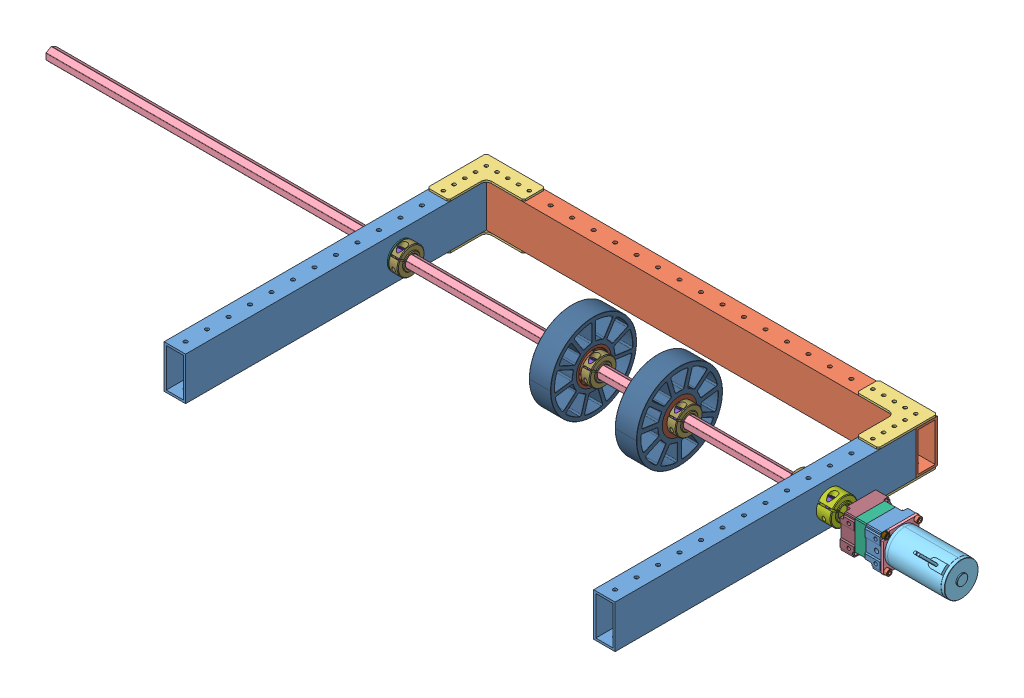
SolidWorks assembly New Intake, configuration Default. Lengths in mm.
Overall size (1077.8 101.6 381).
71 component instances, 30 part files, 56 mates.
Components (placement in the parent):
- 14 in new versaplanetary frame - rev2-1: 14 in new versaplanetary frame - rev2 [Default] at (737.2881 12.7 38.1) x (0 -1 0) z (0 0 -1) size (50.8 25.4 355.6)
- 14 in new versaplanetary frame - rev2-2: 14 in new versaplanetary frame - rev2 [Default] at (1245.2881 12.7 38.1) x (0 1 0) z (0 0 -1) size (50.8 25.4 355.6)
- 21 in new versaplanetary frame - rev2-3: 21 in new versaplanetary frame - rev2 [Default] at (724.5881 12.7 25.4) x (0 -1 0) z (-1 0 0) size (50.8 25.4 533.4)
- VersaFrame 90 Degree Gusset (217-3548).step-1: VersaFrame 90 Degree Gusset (217-3548).step [Default] at (737.2881 -14.986 25.4) x (1 0 0) z (0 1 0) size (69.72 69.72 2.29)
- VersaFrame 90 Degree Gusset (217-3548).step-2: VersaFrame 90 Degree Gusset (217-3548).step [Default] at (737.2881 38.1 25.4) x (1 0 0) z (0 1 0) size (69.72 69.72 2.29)
- VersaFrame 90 Degree Gusset (217-3548).step-3: VersaFrame 90 Degree Gusset (217-3548).step [Default] at (1245.2881 -12.7 25.4) x (-1 0 0) z (0 -1 0) size (69.72 69.72 2.29)
- VersaFrame 90 Degree Gusset (217-3548).step-4: VersaFrame 90 Degree Gusset (217-3548).step [Default] at (1245.2881 40.386 25.4) x (-1 0 0) z (0 -1 0) size (69.72 69.72 2.29)
- half inch hex shaft 36 in long.step-1: half inch hex shaft 36 in long.step [Default] at (794.4381 12.6853 139.7) x (0 -1 0) z (1 0 0) size (14.48 12.67 914.4)
- bearing_0.5in_flangedhex-1: bearing_0.5in_flangedhex [Default] at (1238.4835 12.7 139.7) x (0 0.5 -0.866025) z (-1 0 0) size (31.12 31.12 7.93)
- Half inch flange bearing.step-1: Half inch flange bearing.step [Default] at (743.5848 12.7 139.7) x (0 0 -1) z (1 0 0) size (31.12 31.12 7.93)
- am-1560 500Hex and 500Key Coupler.STEP-1: am-1560 500Hex and 500Key Coupler.STEP [Default] at (1237.7215 21.1345 153.1152) x (1 0 0) z (0 -0.5 -0.866025) size (38.1 31.75 31.68)
  - 500Hex and Key Coupler.STEP-1: 500Hex and Key Coupler.STEP [Default] at (19.05 1.016 15.8425) x (0 0 1) z (-1 0 0) size (31.68 14.86 38.1)
  - 500Hex and Key Coupler.STEP-2: 500Hex and Key Coupler.STEP [Default] at (19.05 1.016 15.8425) x (0 0 -1) z (-1 0 0) size (31.68 14.86 38.1)
  - 10-32x0500_shcs_HX-SHCS 0.19-32x1.375x1-C.STEP-1: 10-32x0500_shcs_HX-SHCS 0.19-32x1.375x1-C.STEP [Default] at (9.525 -8.001 4.73) x (0 1 0) z (-0.057029 0 0.998373) size (17.53 7.94 7.94)
  - 10-32x0500_shcs_HX-SHCS 0.19-32x1.375x1-C.STEP-2: 10-32x0500_shcs_HX-SHCS 0.19-32x1.375x1-C.STEP [Default] at (28.575 -8.001 4.73) x (0 1 0) z (-0.057029 0 0.998373) size (17.53 7.94 7.94)
  - 10-32x0500_shcs_HX-SHCS 0.19-32x1.375x1-C.STEP-3: 10-32x0500_shcs_HX-SHCS 0.19-32x1.375x1-C.STEP [Default] at (28.575 10.033 26.955) x (0 -1 0) z (-0.057029 0 0.998373) size (17.53 7.94 7.94)
  - 10-32x0500_shcs_HX-SHCS 0.19-32x1.375x1-C.STEP-4: 10-32x0500_shcs_HX-SHCS 0.19-32x1.375x1-C.STEP [Default] at (9.525 10.033 26.955) x (0 -1 0) z (-0.057029 0 0.998373) size (17.53 7.94 7.94)
- VersaPlanetary v2 Single Stage 10_1 with BAG .step-1: VersaPlanetary v2 Single Stage 10_1 with BAG .step [Default] at (1308.8383 12.2234 161.9377) x (-1 0 0) z (0 -1 0) size (163.4 66.46 65.46)
  - 217-2820 Rev1_Public.step-1: 217-2820 Rev1_Public.step [Default] at (-4.6546 22.225 0) x (0 -0.456494 0.889726) z (-1 0 0) size (39.22 38.88 17.4)
    - 217-2625-100.step-1: 217-2625-100.step [Default] at origin size (39.22 38.88 12.7)
      - 217-2625-008 Rev1.step-1: 217-2625-008 Rev1.step [Default] at origin size (34.7 34.7 4.7)
      - 217-2625-010 Rev1.step-1: 217-2625-010 Rev1.step [Default] at (0 10.193 3.65) x (0.999813 0.019336 0) z (0 0 1) size (4 4 12)
      - 217-2625-010 Rev1.step-2: 217-2625-010 Rev1.step [Default] at (8.691 -5.3258 3.65) size (4 4 12)
      - 217-2625-010 Rev1.step-3: 217-2625-010 Rev1.step [Default] at (-8.691 -5.3258 3.65) size (4 4 12)
      - 217-2625-005 Rev1_Planet_Revolving_Follower01.step-1: 217-2625-005 Rev1_Planet_Revolving_Follower01.step [Default] at (8.691 -5.3258 6.35) x (0.932816 0.360354 0) z (0 0 1) size (16.89 16.89 8)
      - 217-2625-005 Rev1_Planet_Revolving_Follower01.step-2: 217-2625-005 Rev1_Planet_Revolving_Follower01.step [Default] at (-8.691 -5.3258 6.35) x (-0.932788 -0.360426 0) z (0 0 1) size (16.89 16.89 8)
      - 217-2625-005 Rev1_Planet_Revolving_Follower01.step-3: 217-2625-005 Rev1_Planet_Revolving_Follower01.step [Default] at (0 10.193 6.35) x (0.893583 0.448898 0) z (0 0 1) size (16.89 16.89 8)
    - 217-2625-007 Rev1_Public.step-1: 217-2625-007 Rev1_Public.step [Default] at (0 0 6.7) x (0.992772 0.120019 0) z (0 0 1) size (15.27 15.27 12.7)
  - 217-2625-026 Rev1.step-1: 217-2625-026 Rev1.step [Default] at (-6.5 22.225 0) x (0 -1 0) z (-1 0 0) size (44.45 42 18.12)
  - 217-2742-001 Rev4.step-1: 217-2742-001 Rev4.step [Default] at (0.2002 22.225 0) x (1 0 0) z (0 -0.092627 0.995701) size (7 28 28)
  - 217-2742-001 Rev4.step-2: 217-2742-001 Rev4.step [Default] at (8.2002 22.225 0) size (7 28 28)
  - 217-2625-017 Rev1_9714K61.step-1: 217-2625-017 Rev1_9714K61.step [Default] at (7.42 22.3002 -0.342) x (0 0.56703 0.823697) z (0 -0.823697 0.56703) size (28.51 4.98 27.43)
  - 217-2625-003 Rev1.step-1: 217-2625-003 Rev1.step [Default] at (7.4478 22.225 0) x (0 -1 0) z (1 0 0) size (17 17 64.11)
  - 217-2625-018 Rev1_98541A410.step-1: 217-2625-018 Rev1_98541A410.step [Default] at (-0.7046 22.225 0) x (1 0 0) z (0 -0.017452 0.999848) size (1 19.6 17.4)
  - 832-1750-Ring-Gear-Screw_SSA0832-0500ZC.step-1: 832-1750-Ring-Gear-Screw_SSA0832-0500ZC.step [Default] at (-30.7 4.725 -17.5) x (0 0.997447 0.071411) z (0 -0.071411 0.997447) size (6.73 48.51 6.73)
  - 832-1750-Ring-Gear-Screw_SSA0832-0500ZC.step-2: 832-1750-Ring-Gear-Screw_SSA0832-0500ZC.step [Default] at (-30.7 39.725 17.5) x (0 0.005929 0.999982) z (0 -0.999982 0.005929) size (6.73 48.51 6.73)
  - 217-2625-025 Rev1.step-1: 217-2625-025 Rev1.step [Default] at (-23.2 22.225 0) x (0 -1 0) z (-1 0 0) size (44.45 42 18)
  - 217-4649-002 Rev1_SSA0832-0500ZC.step-1: 217-4649-002 Rev1_SSA0832-0500ZC.step [Default] at (-33.7 4.2645 17.9605) x (0 0.33842 -0.940995) z (0 0.940995 0.33842) size (6.73 16.76 6.73)
  - 217-4649-002 Rev1_SSA0832-0500ZC.step-2: 217-4649-002 Rev1_SSA0832-0500ZC.step [Default] at (-33.7 40.1855 -17.9605) x (0 -0.308932 -0.951084) z (0 0.951084 -0.308932) size (6.73 16.76 6.73)
  - 217-4649-006 Rev1_SSA0004-008BA.step-1: 217-4649-006 Rev1_SSA0004-008BA.step [Default] at (-30.7 22.225 12.5) x (0 0.5 -0.866025) z (0 -0.866025 -0.5) size (7 14 7)
  - 217-4649-006 Rev1_SSA0004-008BA.step-2: 217-4649-006 Rev1_SSA0004-008BA.step [Default] at (-30.7 22.225 -12.5) x (0 -0.5 0.866025) z (0 0.866025 0.5) size (7 14 7)
  - 217-2822-003 Rev4.step-1: 217-2822-003 Rev4.step [Default] at (-32.2 22.225 0) x (0 -1 0) z (-1 0 0) size (42 42 4.8)
  - 217-3351 Rev2.step-1: 217-3351 Rev2.step [Default] at (-33.7 22.225 0) x (0 0 1) z (1 0 0) size (59.07 59.07 84.5)
  - 217-2816-001 Rev1.step-1: 217-2816-001 Rev1.step [Default] at (-6.35 22.225 0) x (0 -1 0) z (1 0 0) size (42 42 14.51)
  - 217-4649-001 Rev1.step-1: 217-4649-001 Rev1.step [Default] at (-20.046 22.225 0) x (0 -1 0) z (1 0 0) size (18 18 13)
  - 217-4649-007 Rev1_94105A824.step-1: 217-4649-007 Rev1_94105A824.step [Default] at (-25.521 22.225 -6.7835) x (-0.996104 -0.088191 0) z (0 0 -1) size (4.83 4.83 4.77)
  - 217-2625-011 Rev1.step-1: 217-2625-011 Rev1.step [Default] at (-24.7818 22.225 0) x (0 0 1) z (0 -1 0) size (8.01 7.5 7.94)
- am-3480 4IN 500Hex Bore Compliant Wheel REV2.STEP-1: am-3480 4IN 500Hex Bore Compliant Wheel REV2.STEP [Default] at (1073.4402 16.5142 123.4245) x (0 0 -1) z (-1 0 0) size (101.6 101.6 25.4)
  - 4IN Compliant Wheel FINAL Overmold.STEP-1: 4IN Compliant Wheel FINAL Overmold.STEP [Default] at (-16.2374 3.8509 18.652) size (101.6 101.6 25.4)
  - 2in Wheel Intergrated 0500 HEX Hub.STEP-1: 2in Wheel Intergrated 0500 HEX Hub.STEP [Default] at (-16.2374 3.8509 5.952) x (-1 0 0) z (0 0 -1) size (41.91 41.91 25.4)
- am-3480 4IN 500Hex Bore Compliant Wheel REV2.STEP-2: am-3480 4IN 500Hex Bore Compliant Wheel REV2.STEP [Default] at (959.9361 8.8125 123.4245) x (0 0 -1) z (1 0 0) size (101.6 101.6 25.4)
  - 4IN Compliant Wheel FINAL Overmold.STEP-1: 4IN Compliant Wheel FINAL Overmold.STEP [Default] at (-16.2374 3.8509 18.652) size (101.6 101.6 25.4)
  - 2in Wheel Intergrated 0500 HEX Hub.STEP-1: 2in Wheel Intergrated 0500 HEX Hub.STEP [Default] at (-16.2374 3.8509 5.952) x (-1 0 0) z (0 0 -1) size (41.91 41.91 25.4)
- am-1526 500Hex HD Collar Clamp.STEP-1: am-1526 500Hex HD Collar Clamp.STEP [Default] at (908.2402 -47.7063 65.4233) x (0 -0.5 -0.866025) z (1 0 0) size (31.73 31.75 12.7)
  - am-1238a 500Hex Collar Clamp Body.STEP-1: am-1238a 500Hex Collar Clamp Body.STEP [Default] at (-94.2794 15.3021 33.01) size (31.73 31.75 12.7)
  - 10-32x0500_shcs_HX-SHCS 0.19-32x1.375x1-C.STEP-1: 10-32x0500_shcs_HX-SHCS 0.19-32x1.375x1-C.STEP [Default] at (-83.1669 24.154 39.36) x (0 -1 0) z (0 0 1) size (17.53 7.94 7.94)
- am-1526 500Hex HD Collar Clamp.STEP-2: am-1526 500Hex HD Collar Clamp.STEP [Default] at (1125.1361 46.573 228.7199) x (0 0.5 0.866025) z (-1 0 0) size (31.73 31.75 12.7)
  - am-1238a 500Hex Collar Clamp Body.STEP-1: am-1238a 500Hex Collar Clamp Body.STEP [Default] at (-94.2794 15.3021 33.01) size (31.73 31.75 12.7)
  - 10-32x0500_shcs_HX-SHCS 0.19-32x1.375x1-C.STEP-1: 10-32x0500_shcs_HX-SHCS 0.19-32x1.375x1-C.STEP [Default] at (-83.1669 24.154 39.36) x (0 -1 0) z (0 0 1) size (17.53 7.94 7.94)
- am-1526 500Hex HD Collar Clamp.STEP-3: am-1526 500Hex HD Collar Clamp.STEP [Default] at (1009.8402 46.6537 50.261) x (0 0.5 -0.866025) z (1 0 0) size (31.73 31.75 12.7)
  - am-1238a 500Hex Collar Clamp Body.STEP-1: am-1238a 500Hex Collar Clamp Body.STEP [Default] at (-94.2794 15.3021 33.01) size (31.73 31.75 12.7)
  - 10-32x0500_shcs_HX-SHCS 0.19-32x1.375x1-C.STEP-1: 10-32x0500_shcs_HX-SHCS 0.19-32x1.375x1-C.STEP [Default] at (-83.1669 24.154 39.36) x (0 -1 0) z (0 0 1) size (17.53 7.94 7.94)
- am-1526 500Hex HD Collar Clamp.STEP-4: am-1526 500Hex HD Collar Clamp.STEP [Default] at (1185.6082 -47.787 65.563) x (0 -0.5 -0.866025) z (1 0 0) size (31.73 31.75 12.7)
  - am-1238a 500Hex Collar Clamp Body.STEP-1: am-1238a 500Hex Collar Clamp Body.STEP [Default] at (-94.2794 15.3021 33.01) size (31.73 31.75 12.7)
  - 10-32x0500_shcs_HX-SHCS 0.19-32x1.375x1-C.STEP-1: 10-32x0500_shcs_HX-SHCS 0.19-32x1.375x1-C.STEP [Default] at (-83.1669 24.154 39.36) x (0 -1 0) z (0 0 1) size (17.53 7.94 7.94)
- am-1526 500Hex HD Collar Clamp.STEP-5: am-1526 500Hex HD Collar Clamp.STEP [Default] at (1023.5361 46.4924 228.8596) x (0 0.5 0.866025) z (-1 0 0) size (31.73 31.75 12.7)
  - am-1238a 500Hex Collar Clamp Body.STEP-1: am-1238a 500Hex Collar Clamp Body.STEP [Default] at (-94.2794 15.3021 33.01) size (31.73 31.75 12.7)
  - 10-32x0500_shcs_HX-SHCS 0.19-32x1.375x1-C.STEP-1: 10-32x0500_shcs_HX-SHCS 0.19-32x1.375x1-C.STEP [Default] at (-83.1669 24.154 39.36) x (0 -1 0) z (0 0 1) size (17.53 7.94 7.94)
- am-1526 500Hex HD Collar Clamp.STEP-6: am-1526 500Hex HD Collar Clamp.STEP [Default] at (796.4601 46.4924 228.8596) x (0 0.5 0.866025) z (-1 0 0) size (31.73 31.75 12.7)
  - am-1238a 500Hex Collar Clamp Body.STEP-1: am-1238a 500Hex Collar Clamp Body.STEP [Default] at (-94.2794 15.3021 33.01) size (31.73 31.75 12.7)
  - 10-32x0500_shcs_HX-SHCS 0.19-32x1.375x1-C.STEP-1: 10-32x0500_shcs_HX-SHCS 0.19-32x1.375x1-C.STEP [Default] at (-83.1669 24.154 39.36) x (0 -1 0) z (0 0 1) size (17.53 7.94 7.94)
Mates (geometry in assembly coordinates):
- Coincident3: coincident anti-aligned: line of 14 in new versaplanetary frame - rev2-1 through (749.9881 38.1 38.1) axis (0 -1 0); plane of 21 in new versaplanetary frame - rev2-3 through (1257.9881 38.1 38.1) normal (0 0 1)
- Coincident4: coincident aligned: plane of 14 in new versaplanetary frame - rev2-1 through (749.9881 38.1 393.7) normal (0 1 0); plane of 21 in new versaplanetary frame - rev2-3 through (1257.9881 38.1 12.7) normal (0 1 0)
- Coincident5: coincident aligned: plane of 14 in new versaplanetary frame - rev2-1 through (724.5881 38.1 393.7) normal (-1 0 0); plane of 21 in new versaplanetary frame - rev2-3 through (724.5881 12.7 25.4) normal (-1 0 0)
- Coincident6: coincident anti-aligned: plane of 14 in new versaplanetary frame - rev2-2 through (1245.2881 12.7 38.1) normal (0 0 -1); plane of 21 in new versaplanetary frame - rev2-3 through (1257.9881 38.1 38.1) normal (0 0 1)
- Coincident7: coincident aligned: plane of 14 in new versaplanetary frame - rev2-2 through (1232.5881 38.1 393.7) normal (0 1 0); plane of 21 in new versaplanetary frame - rev2-3 through (1257.9881 38.1 12.7) normal (0 1 0)
- Coincident9: coincident aligned: plane of 14 in new versaplanetary frame - rev2-2 through (1257.9881 -12.7 393.7) normal (1 0 0); plane of 21 in new versaplanetary frame - rev2-3 through (1257.9881 12.7 25.4) normal (1 0 0)
- Coincident10: coincident anti-aligned: plane of 21 in new versaplanetary frame - rev2-3 through (1257.9881 38.1 12.7) normal (0 1 0); plane of VersaFrame 90 Degree Gusset (217-3548).step-2 through (724.5881 38.1 12.7) normal (0 -1 0)
- Coincident13: coincident anti-aligned: plane of 21 in new versaplanetary frame - rev2-3 through (1257.9881 -12.7 12.7) normal (0 -1 0); plane of VersaFrame 90 Degree Gusset (217-3548).step-1 through (724.5881 -12.7 12.7) normal (0 1 0)
- Coincident17: coincident anti-aligned: plane of 21 in new versaplanetary frame - rev2-3 through (1257.9881 -12.7 12.7) normal (0 -1 0); plane of VersaFrame 90 Degree Gusset (217-3548).step-3 through (1257.9881 -12.7 12.7) normal (0 1 0)
- Coincident18: coincident anti-aligned: plane of 21 in new versaplanetary frame - rev2-3 through (1257.9881 38.1 12.7) normal (0 1 0); plane of VersaFrame 90 Degree Gusset (217-3548).step-4 through (1257.9881 38.1 12.7) normal (0 -1 0)
- Coincident20: coincident anti-aligned: plane of 21 in new versaplanetary frame - rev2-3 through (1257.9881 38.1 12.7) normal (0 1 0); plane of VersaFrame 90 Degree Gusset (217-3548).step-2 through (724.5881 38.1 12.7) normal (0 -1 0)
- Concentric8: concentric anti-aligned: cylinder of 21 in new versaplanetary frame - rev2-3 through (1245.2881 -12.7 25.4) axis (0 -1 0) radius 2.2479; cylinder of VersaFrame 90 Degree Gusset (217-3548).step-4 through (1245.2881 38.1 25.4) axis (0 1 0) radius 2.0701
- Concentric9: concentric aligned: cylinder of 14 in new versaplanetary frame - rev2-2 through (1245.2881 38.1 76.2) axis (0 1 0) radius 2.2479; cylinder of VersaFrame 90 Degree Gusset (217-3548).step-4 through (1245.2881 38.1 76.2) axis (0 1 0) radius 2.0701
- Coincident23: coincident anti-aligned: plane of 14 in new versaplanetary frame - rev2-2 through (1232.5881 -12.7 393.7) normal (-1 0 0); circle of bearing_0.5in_flangedhex-1
- Concentric16: concentric aligned: cylinder of 14 in new versaplanetary frame - rev2-2 through (1257.9881 12.7 139.7) axis (1 0 0) radius 12.7; cylinder of bearing_0.5in_flangedhex-1 through (1230.5561 12.7 139.7) axis (1 0 0) radius 14.2875
- Coincident24: coincident anti-aligned: plane of 14 in new versaplanetary frame - rev2-1 through (749.9881 38.1 393.7) normal (1 0 0); plane of Half inch flange bearing.step-1 through (749.9881 12.7 125.73) normal (-1 0 0)
- Concentric17: concentric aligned: cylinder of 14 in new versaplanetary frame - rev2-1 through (724.5881 12.7 139.7) axis (-1 0 0) radius 12.7; cylinder of Half inch flange bearing.step-1 through (751.5121 12.7 139.7) axis (-1 0 0) radius 14.2875
- Coincident27: coincident anti-aligned: plane of half inch hex shaft 36 in long.step-1 through (1251.6381 5.3677 139.7) normal (0 -0.866025 -0.5); plane of bearing_0.5in_flangedhex-1 through (1230.5561 5.3677 139.7) normal (0 0.866025 0.5)
- Coincident29: coincident anti-aligned: plane of half inch hex shaft 36 in long.step-1 through (1251.6381 9.0265 146.0373) normal (0 -0.866025 0.5); plane of bearing_0.5in_flangedhex-1 through (1230.5561 9.0338 146.05) normal (0 0.866025 -0.5)
- Distance1: distance = 6.35 mm aligned: plane of half inch hex shaft 36 in long.step-1 through (1251.6381 5.3677 139.7) normal (1 0 0); plane of 14 in new versaplanetary frame - rev2-2 through (1257.9881 -12.7 393.7) normal (1 0 0)
- Concentric18: concentric anti-aligned: cylinder of 21 in new versaplanetary frame - rev2-3 through (1245.2881 -12.7 25.4) axis (0 -1 0) radius 2.2479; cylinder of VersaFrame 90 Degree Gusset (217-3548).step-3 through (1245.2881 -14.986 25.4) axis (0 1 0) radius 2.0701
- Concentric19: concentric aligned: cylinder of 21 in new versaplanetary frame - rev2-3 through (737.2881 -12.7 25.4) axis (0 -1 0) radius 2.2479; cylinder of VersaFrame 90 Degree Gusset (217-3548).step-1 through (737.2881 -12.7 25.4) axis (0 -1 0) radius 2.0701
- Concentric20: concentric aligned: cylinder of 14 in new versaplanetary frame - rev2-1 through (737.2881 -12.7 76.2) axis (0 -1 0) radius 2.2479; cylinder of VersaFrame 90 Degree Gusset (217-3548).step-1 through (737.2881 -12.7 76.2) axis (0 -1 0) radius 2.0701
- Concentric21: concentric aligned: cylinder of 21 in new versaplanetary frame - rev2-3 through (737.2881 -12.7 25.4) axis (0 -1 0) radius 2.2479; cylinder of VersaFrame 90 Degree Gusset (217-3548).step-2 through (737.2881 40.386 25.4) axis (0 -1 0) radius 2.0701
- Concentric22: concentric aligned: cylinder of 14 in new versaplanetary frame - rev2-1 through (737.2881 -12.7 76.2) axis (0 -1 0) radius 2.2479; cylinder of VersaFrame 90 Degree Gusset (217-3548).step-2 through (737.2881 40.386 76.2) axis (0 -1 0) radius 2.0701
- Coincident30: coincident anti-aligned: plane of bearing_0.5in_flangedhex-1 through (1238.4835 12.7 139.7) normal (1 0 0); plane of am-1560 500Hex and 500Key Coupler.STEP-1/500Hex and Key Coupler.STEP-1 through (1238.4835 12.3334 139.9032) normal (-1 0 0)
- Coincident31: coincident anti-aligned: plane of half inch hex shaft 36 in long.step-1 through (1251.6381 9.0265 133.3627) normal (0 0 -1); plane of am-1560 500Hex and 500Key Coupler.STEP-1/500Hex and Key Coupler.STEP-2 through (1275.8215 16.1095 133.3627) normal (0 0 1)
- Coincident32: coincident anti-aligned: plane of half inch hex shaft 36 in long.step-1 through (1251.6381 20.003 139.7) normal (0 0.866025 0.5); plane of am-1560 500Hex and 500Key Coupler.STEP-1/500Hex and Key Coupler.STEP-2 through (1275.8215 16.1095 146.4437) normal (0 -0.866025 -0.5)
- Coincident35: coincident anti-aligned: plane of half inch hex shaft 36 in long.step-1 through (1251.6381 5.3677 139.7) normal (1 0 0); plane of VersaPlanetary v2 Single Stage 10_1 with BAG .step-1/217-2625-003 Rev1.step-1 through (1251.6381 8.5572 133.3627) normal (-1 0 0)
- Coincident36: coincident anti-aligned: plane of am-1560 500Hex and 500Key Coupler.STEP-1/500Hex and Key Coupler.STEP-1 through (1275.8215 8.5572 133.3627) normal (0 0.866025 0.5); plane of VersaPlanetary v2 Single Stage 10_1 with BAG .step-1/217-2625-003 Rev1.step-1 through (1251.6381 8.5572 133.3627) normal (0 -0.866025 -0.5)
- Coincident40: coincident anti-aligned: plane of am-1560 500Hex and 500Key Coupler.STEP-1/500Hex and Key Coupler.STEP-2 through (1275.8215 16.1095 133.3627) normal (0 0 1); plane of VersaPlanetary v2 Single Stage 10_1 with BAG .step-1/217-2625-003 Rev1.step-1 through (1251.6381 15.8896 133.3627) normal (0 0 -1)
- Parallel3: parallel aligned: plane of 14 in new versaplanetary frame - rev2-2 through (1232.5881 38.1 393.7) normal (0 1 0); plane of VersaPlanetary v2 Single Stage 10_1 with BAG .step-1/217-2625-026 Rev1.step-1 through (1310.3383 33.2234 160.7127) normal (0 1 0)
- Coincident42: coincident anti-aligned: plane of half inch hex shaft 36 in long.step-1 through (1251.6381 16.3442 146.0373) normal (0 0 1); plane of am-3480 4IN 500Hex Bore Compliant Wheel REV2.STEP-1/2in Wheel Intergrated 0500 HEX Hub.STEP-1 through (1080.1881 8.9825 146.0373) normal (0 0 -1)
- Coincident43: coincident anti-aligned: plane of half inch hex shaft 36 in long.step-1 through (1251.6381 20.003 139.7) normal (0 0.866025 0.5); plane of am-3480 4IN 500Hex Bore Compliant Wheel REV2.STEP-1/2in Wheel Intergrated 0500 HEX Hub.STEP-1 through (1080.1881 16.3442 146.0373) normal (0 -0.866025 -0.5)
- Distance2: distance = 152.4 mm anti-aligned: plane of 14 in new versaplanetary frame - rev2-2 through (1232.5881 -12.7 393.7) normal (-1 0 0); plane of am-3480 4IN 500Hex Bore Compliant Wheel REV2.STEP-1/2in Wheel Intergrated 0500 HEX Hub.STEP-1 through (1080.1881 10.1233 139.6619) normal (1 0 0)
- Coincident45: coincident anti-aligned: plane of half inch hex shaft 36 in long.step-1 through (1251.6381 16.3442 146.0373) normal (0 0 1); plane of am-3480 4IN 500Hex Bore Compliant Wheel REV2.STEP-2/2in Wheel Intergrated 0500 HEX Hub.STEP-1 through (953.1881 16.3442 146.0373) normal (0 0 -1)
- Coincident46: coincident anti-aligned: plane of half inch hex shaft 36 in long.step-1 through (1251.6381 20.003 139.7) normal (0 0.866025 0.5); plane of am-3480 4IN 500Hex Bore Compliant Wheel REV2.STEP-2/2in Wheel Intergrated 0500 HEX Hub.STEP-1 through (953.1881 20.025 139.6619) normal (0 -0.866025 -0.5)
- Distance3: distance = 203.2 mm anti-aligned: plane of am-3480 4IN 500Hex Bore Compliant Wheel REV2.STEP-2/2in Wheel Intergrated 0500 HEX Hub.STEP-1 through (953.1881 15.2033 139.6619) normal (-1 0 0); plane of 14 in new versaplanetary frame - rev2-1 through (749.9881 38.1 393.7) normal (1 0 0)
- Coincident48: coincident anti-aligned: plane of am-3480 4IN 500Hex Bore Compliant Wheel REV2.STEP-2/2in Wheel Intergrated 0500 HEX Hub.STEP-1 through (953.1881 15.2033 139.6619) normal (-1 0 0); plane of am-1526 500Hex HD Collar Clamp.STEP-1/am-1238a 500Hex Collar Clamp Body.STEP-1 through (953.1881 12.6853 139.4206) normal (1 0 0)
- Coincident49: coincident anti-aligned: plane of half inch hex shaft 36 in long.step-1 through (1251.6381 20.003 139.7) normal (0 0.866025 0.5); plane of am-1526 500Hex HD Collar Clamp.STEP-1/am-1238a 500Hex Collar Clamp Body.STEP-1 through (941.2501 20.1643 139.4206) normal (0 -0.866025 -0.5)
- Coincident50: coincident anti-aligned: plane of half inch hex shaft 36 in long.step-1 through (1251.6381 9.0265 146.0373) normal (0 -0.866025 0.5); plane of am-1526 500Hex HD Collar Clamp.STEP-1/am-1238a 500Hex Collar Clamp Body.STEP-1 through (941.2501 8.9458 145.8976) normal (0 0.866025 -0.5)
- Coincident52: coincident anti-aligned: plane of am-3480 4IN 500Hex Bore Compliant Wheel REV2.STEP-1/2in Wheel Intergrated 0500 HEX Hub.STEP-1 through (1080.1881 10.1233 139.6619) normal (1 0 0); plane of am-1526 500Hex HD Collar Clamp.STEP-2/am-1238a 500Hex Collar Clamp Body.STEP-1 through (1080.1881 12.6853 139.4206) normal (-1 0 0)
- Coincident53: coincident anti-aligned: plane of half inch hex shaft 36 in long.step-1 through (1251.6381 9.0265 146.0373) normal (0 -0.866025 0.5); plane of am-1526 500Hex HD Collar Clamp.STEP-2/am-1238a 500Hex Collar Clamp Body.STEP-1 through (1092.1261 5.2063 139.4206) normal (0 0.866025 -0.5)
- Coincident54: coincident anti-aligned: plane of half inch hex shaft 36 in long.step-1 through (1251.6381 20.003 139.7) normal (0 0.866025 0.5); plane of am-1526 500Hex HD Collar Clamp.STEP-2/am-1238a 500Hex Collar Clamp Body.STEP-1 through (1092.1261 16.4248 145.8976) normal (0 -0.866025 -0.5)
- Coincident55: coincident anti-aligned: plane of am-3480 4IN 500Hex Bore Compliant Wheel REV2.STEP-1/2in Wheel Intergrated 0500 HEX Hub.STEP-1 through (1054.7881 10.1233 139.6619) normal (-1 0 0); plane of am-1526 500Hex HD Collar Clamp.STEP-3/am-1238a 500Hex Collar Clamp Body.STEP-1 through (1054.7881 12.766 139.5603) normal (1 0 0)
- Coincident56: coincident anti-aligned: plane of half inch hex shaft 36 in long.step-1 through (1251.6381 9.0265 146.0373) normal (0 -0.866025 0.5); plane of am-1526 500Hex HD Collar Clamp.STEP-3/am-1238a 500Hex Collar Clamp Body.STEP-1 through (1042.8501 9.0265 146.0373) normal (0 0.866025 -0.5)
- Coincident57: coincident anti-aligned: plane of half inch hex shaft 36 in long.step-1 through (1251.6381 16.3442 146.0373) normal (0 0 1); plane of am-1526 500Hex HD Collar Clamp.STEP-3/am-1238a 500Hex Collar Clamp Body.STEP-1 through (1042.8501 16.5055 146.0373) normal (0 0 -1)
- Coincident58: coincident anti-aligned: plane of am-3480 4IN 500Hex Bore Compliant Wheel REV2.STEP-2/2in Wheel Intergrated 0500 HEX Hub.STEP-1 through (978.5881 15.2033 139.6619) normal (1 0 0); plane of am-1526 500Hex HD Collar Clamp.STEP-5/am-1238a 500Hex Collar Clamp Body.STEP-1 through (978.5881 12.6047 139.5603) normal (-1 0 0)
- Coincident59: coincident anti-aligned: plane of half inch hex shaft 36 in long.step-1 through (1251.6381 20.003 139.7) normal (0 0.866025 0.5); plane of am-1526 500Hex HD Collar Clamp.STEP-5/am-1238a 500Hex Collar Clamp Body.STEP-1 through (990.5261 16.3442 146.0373) normal (0 -0.866025 -0.5)
- Coincident62: coincident anti-aligned: plane of half inch hex shaft 36 in long.step-1 through (1251.6381 16.3442 146.0373) normal (0 0 1); plane of am-1526 500Hex HD Collar Clamp.STEP-5/am-1238a 500Hex Collar Clamp Body.STEP-1 through (990.5261 8.8652 146.0373) normal (0 0 -1)
- Coincident63: coincident anti-aligned: plane of Half inch flange bearing.step-1 through (751.5121 12.7 124.1425) normal (1 0 0); plane of am-1526 500Hex HD Collar Clamp.STEP-6/am-1238a 500Hex Collar Clamp Body.STEP-1 through (751.5121 -3.1775 139.5603) normal (-1 0 0)
- Coincident64: coincident anti-aligned: plane of half inch hex shaft 36 in long.step-1 through (1251.6381 16.3442 146.0373) normal (0 0 1); plane of am-1526 500Hex HD Collar Clamp.STEP-6/am-1238a 500Hex Collar Clamp Body.STEP-1 through (763.4501 -6.917 146.0373) normal (0 0 -1)
- Coincident66: coincident anti-aligned: plane of half inch hex shaft 36 in long.step-1 through (1251.6381 20.003 139.7) normal (0 0.866025 0.5); plane of am-1526 500Hex HD Collar Clamp.STEP-6/am-1238a 500Hex Collar Clamp Body.STEP-1 through (763.4501 16.3442 146.0373) normal (0 -0.866025 -0.5)
- Coincident67: coincident: plane of bearing_0.5in_flangedhex-1 through (1230.5561 20.4788 126.2268) normal (-1 0 0); plane of am-1526 500Hex HD Collar Clamp.STEP-4/am-1238a 500Hex Collar Clamp Body.STEP-1 through (1230.5561 12.6047 139.5603) normal (1 0 0)
- Coincident68: coincident: plane of half inch hex shaft 36 in long.step-1 through (1251.6381 20.003 139.7) normal (0 0.866025 0.5); plane of am-1526 500Hex HD Collar Clamp.STEP-4/am-1238a 500Hex Collar Clamp Body.STEP-1 through (1218.6181 20.0837 139.5603) normal (0 -0.866025 -0.5)
- Coincident69: coincident anti-aligned: plane of half inch hex shaft 36 in long.step-1 through (1251.6381 16.3442 146.0373) normal (0 0 1); plane of am-1526 500Hex HD Collar Clamp.STEP-4/am-1238a 500Hex Collar Clamp Body.STEP-1 through (1218.6181 16.3442 146.0373) normal (0 0 -1)
